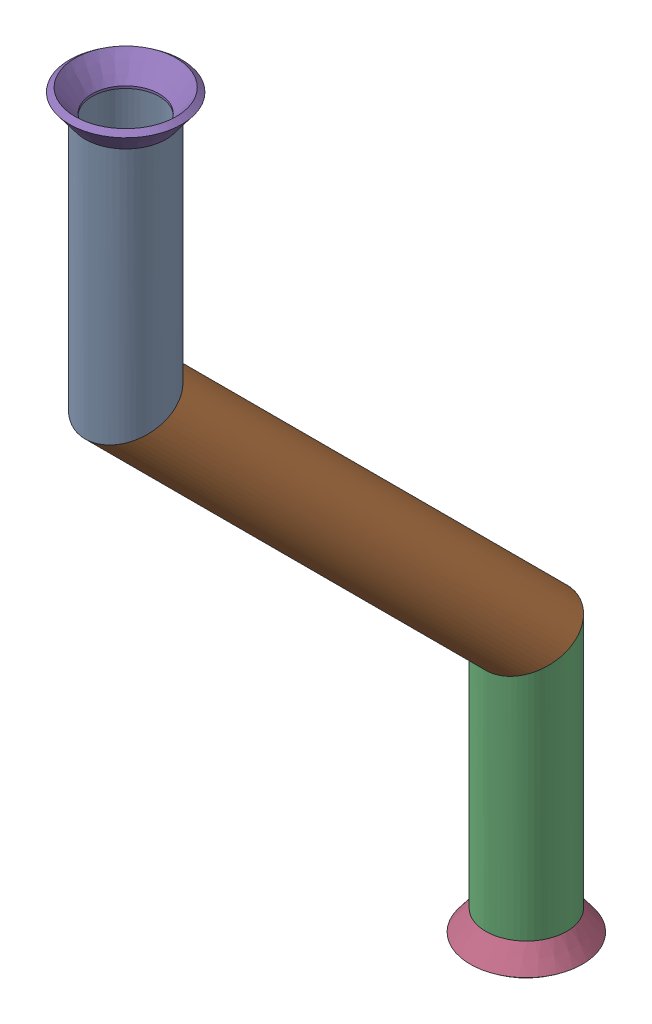
SolidWorks assembly Pipe 19, configuration Default. Lengths in mm.
Overall size (17.59 146.84 80.46).
3 component instances, 2 part files, 4 mates.
Components (placement in the parent):
- Part2-1: Part2 [Default<As Machined>] at origin size (12.7 139.06 75.56)
- Flared pipe end - .5 inch-1: Flared pipe end - .5 inch [Default<As Machined>] at (0 -189.578 244.7365) x (1 0 -0.00017) z (0 -1 0) size (17.59 17.59 3.89)
- Flared pipe end - .5 inch-2: Flared pipe end - .5 inch [Default<As Machined>] at (0 -50.5162 307.5983) x (1 0 0.00017) z (0 1 0) size (17.59 17.59 3.89)
Mates (geometry in assembly coordinates):
- Coincident1029: coincident: plane of Part2-1 through (0 -189.578 244.7365) normal (0 -1 0); plane of Flared pipe end - .5 inch-1 through (0.0009 -189.578 250.0197) normal (0 1 0)
- Concentric657: concentric: circle of Part2-1; circle of Flared pipe end - .5 inch-1
- Coincident1027: coincident: plane of Part2-1 through (0 -50.5162 307.5983) normal (0 1 0); plane of Flared pipe end - .5 inch-2 through (0.0009 -50.5162 302.3151) normal (0 -1 0)
- Concentric656: concentric: circle of Part2-1; circle of Flared pipe end - .5 inch-2
